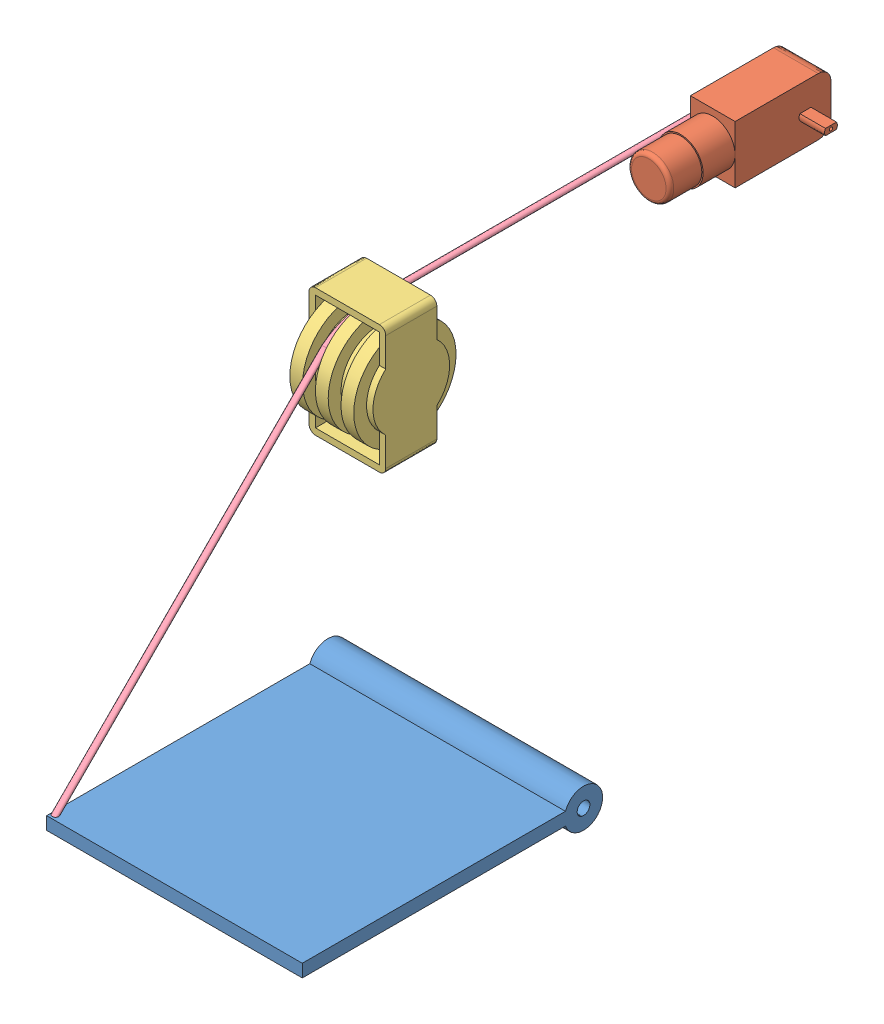
SolidWorks assembly updated_drawbridge, configuration Default. Lengths in mm.
Overall size (108.35 132.87 284.4).
4 component instances, 4 part files, 0 mates.
Components (placement in the parent):
- updated_drawbridge_1-1: updated_drawbridge_1 [Default] at (-93.5558 -18.0141 -16.0277) size (100 15 117.5)
- motor_placeholder-1: motor_placeholder [Default] at (-88.6603 96.1076 -171.6744) size (37.5 22.5 62.5)
- Pulley_1-1: Pulley_1 [Default] at (-101.9064 79.901 -27.0185) size (30 50 40)
- rope4-1: rope4 [Default] at (-92.1208 -16.0997 92.4998) size (2.72 113.45 276.85)
